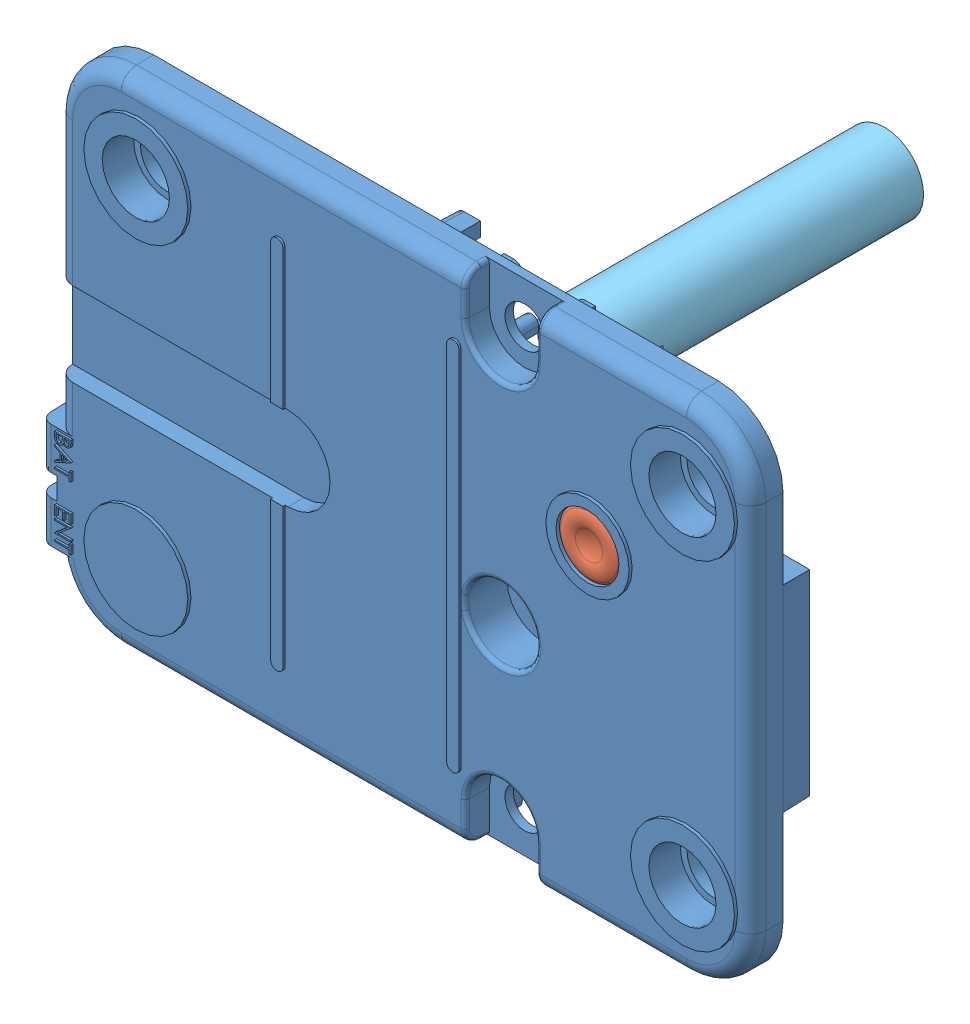
SolidWorks assembly 706000, configuration Default. Lengths in mm.
Overall size (86.66 60.96 57.16).
6 component instances, 6 part files, 21 mates.
Components (placement in the parent):
- 705031-1: 705031 [Default] at origin size (86.66 60.96 12.95)
- 705052-1: 705052 [Deformed] at (-11.5824 -11.2776 -2.4698) x (0 0 -1) z (0.464477 -0.885585 0) size (0.89 7.54 7.54)
- 705053-2: 705053 [Deflected] at (-34.9631 -13.0556 3.1623) size (42.18 16.65 6.26)
- 705054-1: 705054 [Solid] at (-11.5824 -11.2776 1.9076) x (0.361129 -0.932516 0) z (-0.932516 -0.361129 0) size (3.56 2.04 3.56)
- 705055-1: 705055 [Default] at (-11.5824 -11.2776 3.048) x (0 0 -1) z (0.20832 0.978061 0) size (5.33 4.72 4.72)
- 756000 Stake removal tool PULL-1: 756000 Stake removal tool PULL [Default] at (-32.5131 -10.8211 -52.832) x (0 -1 0) z (0 0 1) size (9.53 9.53 38.1)
Mates (geometry in assembly coordinates):
- Width1: width: plane of 705031-1 through (-50.8889 -14.0208 1.524) normal (0.99999 0 -0.004363); plane of 705031-1 through (-50.0253 -14.0208 1.524) normal (-0.99999 0 -0.004363); cylinder of ? through (-50.4571 -12.4587 1.1303) axis (0 -1 0) radius 0.3937
- Width2: width: plane of 705031-1 through (-29.464 -10.8458 1.778) normal (0 -0.99999 -0.004363); plane of 705031-1 through (-35.56 -11.7094 1.778) normal (0 0.99999 -0.004363); cylinder of ? through (-49.309 -11.2776 0.8532) axis (0.97208 0 -0.234649) radius 0.3937
- Tangent1: tangent anti-aligned: plane of 705031-1 through (-48.7426 -20.6248 1.778) normal (0 0 -1); cylinder of 705053-2 through (-49.276 -11.2776 1.3843) axis (1 0 0) radius 0.3937
- Concentric1: concentric anti-aligned: cone of 705031-1 through (-11.5824 -11.2776 -1.397) axis (0 0 -1); cylinder of 705055-1 through (-11.5824 -11.2776 3.048) axis (0 0 1) radius 2.3622
- Coincident1: coincident anti-aligned: line of 705054-1 through (-11.5824 -11.2776 64.5888) axis (0 0 -1); axis of 705055-1 through (-11.5824 -11.2776 1.143) axis (0 0 1)
- Concentric2: concentric: cylinder of 705031-1 through (-11.5824 -11.2776 3.683) axis (0 0 1) radius 3.8354; cone of 705052-1 through (-11.5824 -11.2776 3.683) axis (0 0 -1)
- Coincident2: coincident aligned: plane of 705031-1 through (-6.5679 -12.0396 -2.286) normal (0 0 -1); plane of 705055-1 through (-12.9488 -10.9866 -2.286) normal (0 0 -1)
- Coincident3: coincident: plane of assembly; point of 705054-1; plane of 705055-1 through (-13.3959 -10.8913 1.524) normal (0 0 1)
- Coincident4: coincident anti-aligned: plane of 705031-1 through (-11.5824 -11.2776 3.683) normal (0 0 1); circle of 705052-1
- Parallel1: parallel: line of 705031-1 through (33.3756 -76.6826 1.9812) axis (0 0 -1); line of ? through (-50.4571 -12.4587 1.1303) axis (0 -1 0)
- Width3: width: plane of 705031-1 through (-29.464 -10.8458 1.778) normal (0 -0.99999 -0.004363); plane of 705031-1 through (-35.56 -11.7094 1.778) normal (0 0.99999 -0.004363); cylinder of 705053-2 through (-49.276 -11.2776 1.3843) axis (1 0 0) radius 0.3937
- Width4: width: plane of 705031-1 through (-50.0253 -14.0208 1.524) normal (-0.99999 0 -0.004363); plane of 705031-1 through (-50.8889 -14.0208 1.524) normal (0.99999 0 -0.004363); cylinder of 705053-2 through (-50.4571 -12.4587 1.3843) axis (0 -1 0) radius 0.3937
- Tangent2: tangent anti-aligned: plane of 705031-1 through (-48.7426 -20.6248 1.778) normal (0 0 -1); cylinder of 705053-2 through (-49.276 -11.2776 1.3843) axis (1 0 0) radius 0.3937
- Parallel2: parallel aligned: line of 705031-1 through (33.3756 -76.6826 1.9812) axis (0 0 -1); line of 705053-2 through (-50.4571 -12.4587 1.3843) axis (0 -1 0)
- Parallel3: parallel anti-aligned: plane of 705031-1 through (-22.5298 4.7752 2.54) normal (0 0 -1); plane of 756000 Stake removal tool PULL-1 through (-29.2111 -4.5631 -15.24) normal (0 0 1)
- Width5: width anti-aligned: plane of 756000 Stake removal tool PULL-1 through (-29.2111 -10.1099 -21.082) normal (-1 0 0); plane of 756000 Stake removal tool PULL-1 through (-35.8151 -10.1099 -21.082) normal (1 0 0); plane of 705031-1 through (-35.56 -11.7094 2.54) normal (-0.99999 0 -0.004363); plane of 705031-1 through (-29.464 0.635 3.048) normal (0.99999 0 -0.004363)
- Distance1: distance = 17.78 mm anti-aligned: plane of 756000 Stake removal tool PULL-1 through (-29.2111 -4.5631 -15.24) normal (0 0 1); plane of 705031-1 through (-22.5298 4.7752 2.54) normal (0 0 -1)
- Tangent3: tangent: plane of 705031-1 through (-50.0253 -27.2288 1.524) normal (0 0 -1); cylinder of ? through (-50.4571 -12.4587 1.1303) axis (0 -1 0) radius 0.3937
- Distance2: distance = 1.4728 mm: moEndPointRef_w of ?; plane of 705031-1 through (-6.5679 -12.0396 -2.286) normal (0 0 -1)
- Coincident7: coincident anti-aligned: plane of 705031-1 through (-11.5824 -11.2776 3.683) normal (0 0 1); circle of 705052-1
- Concentric3: concentric anti-aligned: circle of 705031-1; circle of 705052-1
